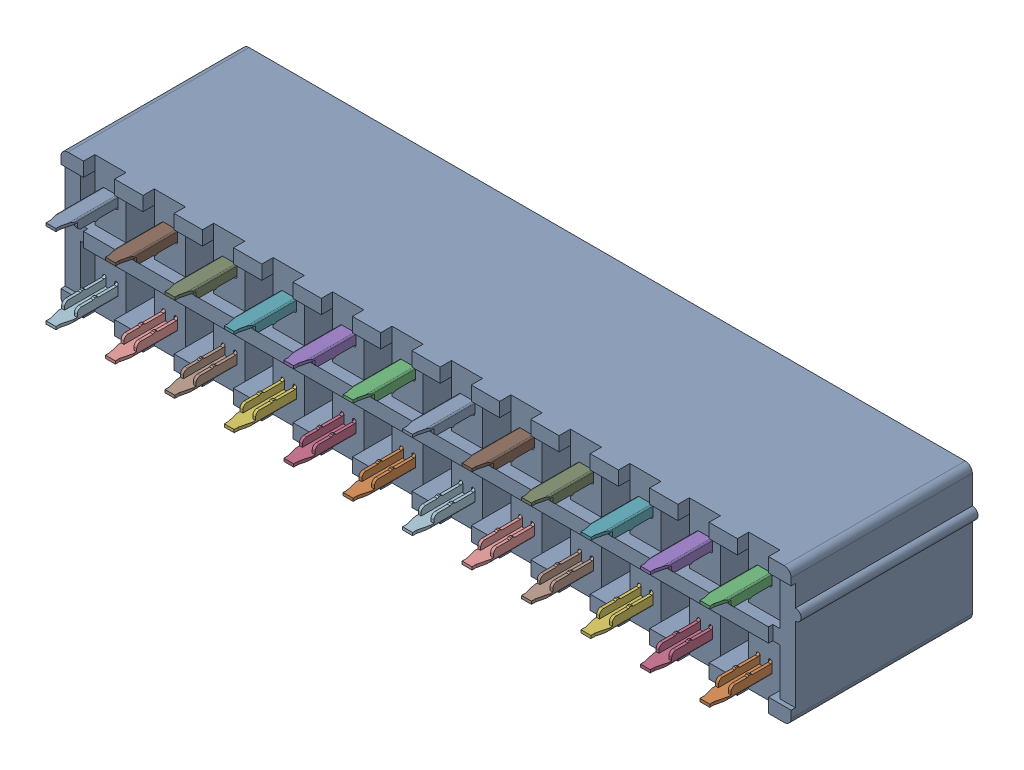
SolidWorks assembly 24P I Motherboard Power connector withoout lock v2, configuration Valor predeterminado. Lengths in mm.
Overall size (52 11 16.2).
13 component instances, 2 part files, 0 mates.
Components (placement in the parent):
- housing 24P I withoout lock-1: housing 24P I withoout lock [Valor predeterminado] at origin size (52 11 12.8)
- one set of pins I-1: one set of pins I [Valor predeterminado] at (42.2955 0.8635 0) size (1.1 6.2 12.6)
- one set of pins I-2: one set of pins I [Valor predeterminado] at (38.0955 0.8635 0) size (1.1 6.2 12.6)
- one set of pins I-3: one set of pins I [Valor predeterminado] at (33.8955 0.8635 0) size (1.1 6.2 12.6)
- one set of pins I-4: one set of pins I [Valor predeterminado] at (29.6955 0.8635 0) size (1.1 6.2 12.6)
- one set of pins I-5: one set of pins I [Valor predeterminado] at (25.4955 0.8635 0) size (1.1 6.2 12.6)
- one set of pins I-6: one set of pins I [Valor predeterminado] at (21.2955 0.8635 0) size (1.1 6.2 12.6)
- one set of pins I-7: one set of pins I [Valor predeterminado] at (17.0955 0.8635 0) size (1.1 6.2 12.6)
- one set of pins I-8: one set of pins I [Valor predeterminado] at (12.8955 0.8635 0) size (1.1 6.2 12.6)
- one set of pins I-9: one set of pins I [Valor predeterminado] at (8.6955 0.8635 0) size (1.1 6.2 12.6)
- one set of pins I-10: one set of pins I [Valor predeterminado] at (4.4955 0.8635 0) size (1.1 6.2 12.6)
- one set of pins I-11: one set of pins I [Valor predeterminado] at (0.2955 0.8635 0) size (1.1 6.2 12.6)
- one set of pins I-12: one set of pins I [Valor predeterminado] at (-3.9045 0.8635 0) size (1.1 6.2 12.6)
